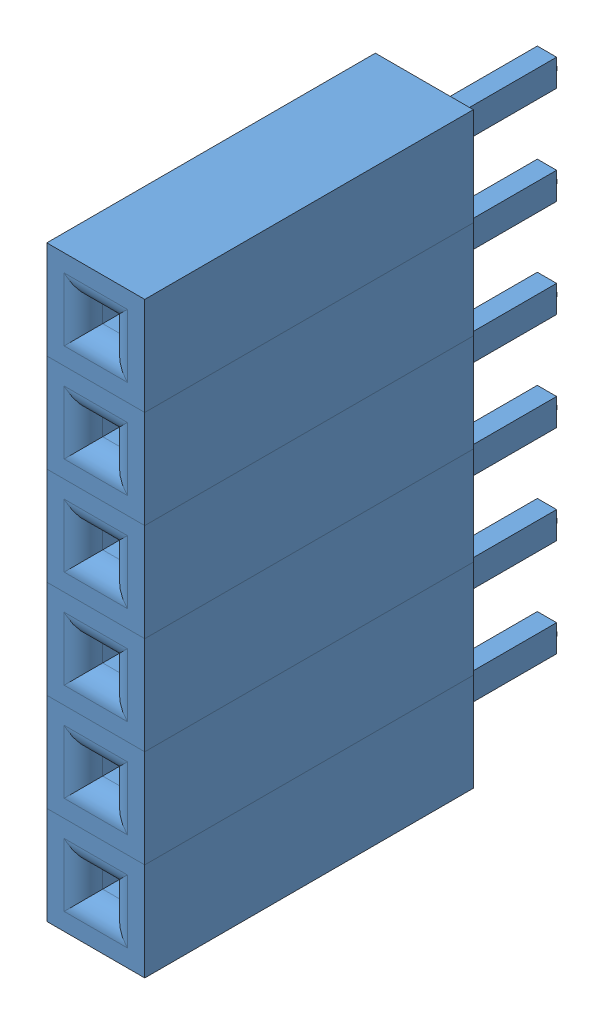
SolidWorks assembly Assem8, configuration Default. Lengths in mm.
Overall size (2.54 15.24 11.8).
6 component instances, 1 part files, 0 mates.
Components (placement in the parent):
- Female Header Pin-1: Female Header Pin [Default] at (-1.3245 1.2101 -2.7432) size (2.54 2.54 11.8)
- Female Header Pin-2: Female Header Pin [Default] at (-1.3245 3.7501 -2.7432) size (2.54 2.54 11.8)
- Female Header Pin-3: Female Header Pin [Default] at (-1.3245 6.2901 -2.7432) size (2.54 2.54 11.8)
- Female Header Pin-4: Female Header Pin [Default] at (-1.3245 8.8301 -2.7432) size (2.54 2.54 11.8)
- Female Header Pin-5: Female Header Pin [Default] at (-1.3245 11.3701 -2.7432) size (2.54 2.54 11.8)
- Female Header Pin-6: Female Header Pin [Default] at (-1.3245 13.9101 -2.7432) size (2.54 2.54 11.8)
